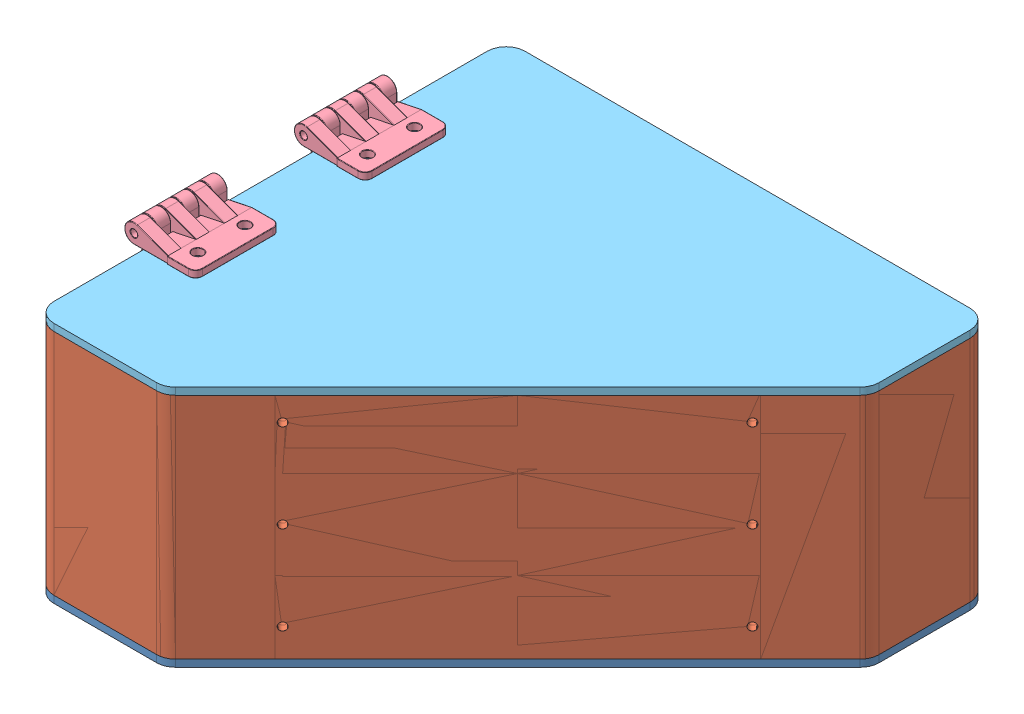
SolidWorks assembly assieme3, configuration Default. Lengths in mm.
Overall size (239.18 111 212.11).
9 component instances, 5 part files, 16 mates.
Components (placement in the parent):
- sotto-1: sotto [Default] at (-155.9057 -26.2592 100) size (205 3 200)
- sopra-1: sopra [Default] at (-155.9057 -26.2592 100) size (237.93 97 212.11)
- middle-1: middle [Default] at (43.7198 44.7408 -93.5026) x (0 0 1) z (0 -1 0) size (187 193 5)
- hinge-2: hinge [Default] at (-155.9057 54.2981 -18) x (0 1 0) z (0 0 1) size (30.44 8 36)
- lid-1: lid [Default] at (-155.9057 73.7408 100) x (1 0 0) z (0 1 0) size (205 200 3)
- hinge-6: hinge [Default] at (-133.4631 76.7408 -53.7) x (-1 0 0) z (0 0 -1) size (30.44 8 36)
- hinge-7: hinge [Default] at (-133.4631 76.7408 18.3) x (-1 0 0) z (0 0 -1) size (30.44 8 36)
- hinge-8: hinge [Default] at (-155.9057 54.2981 54) x (0 1 0) z (0 0 1) size (30.44 8 36)
- sopra-2: sopra [Default] at (-155.9057 -26.2592 100) size (237.93 97 212.11)
Mates (geometry in assembly coordinates):
- Concentrico1: concentric aligned: cylinder of sotto-1 through (-102.1147 -26.2592 97.0813) axis (0 -1 0) radius 1.65; cylinder of sopra-1 through (-102.1147 -26.2592 97.0813) axis (0 -1 0) radius 1.65
- Coincidente1: coincident aligned: plane of sotto-1 through (-155.9057 73.7408 92) normal (-1 0 0); plane of sopra-1 through (-155.9057 73.7408 92) normal (-1 0 0)
- Coincidente2: coincident anti-aligned: plane of sopra-1 through (-135.9057 39.7408 -80) normal (0 1 0); plane of layer2.2-1 through (-141.2802 39.7408 -85.5026) normal (0 -1 0)
- Coincidente5: coincident: plane of sotto-1 through (-155.9057 -23.2592 100.01) normal (0 1 0); line of sopra-1 through (-77.4618 -23.2592 76.5561) axis (0.707107 0 -0.707107)
- Concentrico4: concentric aligned: circle of sopra-1; circle of layer2.2-1
- Coincidente24: coincident anti-aligned: plane of hinge-4 through (-152.9057 88.5408 15) normal (-1 0 0); plane of lid prova-1 through (-104.2195 73.7408 92) normal (0 -1 0)
- Coincidente103: coincident: plane of sopra-1 through (-155.9057 73.7408 92) normal (-1 0 0); plane of hinge-2 through (-155.9057 80.7408 -54) normal (1 0 0)
- Concentrico14: concentric: cylinder of hinge-2 through (-159.9057 80.7408 -54) axis (0 0 1) radius 1.5; cylinder of hinge-6 through (-159.9057 80.7408 -17.7) axis (0 0 -1) radius 1.5
- Coincidente105: coincident anti-aligned: plane of lid prova-1 through (-104.2195 76.7408 92) normal (0 1 0); plane of hinge-6 through (-159.9057 76.7408 -17.7) normal (0 -1 0)
- Coincidente115: coincident: plane of hinge-2 through (-159.9057 80.7408 -53.7) normal (0 0 -1); plane of hinge-6 through (-159.9057 80.7408 -53.7) normal (0 0 -1)
- Distanza9: distance = 8 mm: line of sopra-1 through (-155.9057 73.7408 -62) axis (0 -1 0); plane of hinge-2 through (-159.9057 80.7408 -54) normal (0 0 -1)
- Concentrico15: concentric: cylinder of sopra-1 through (-155.9057 61.2981 26) axis (-1 0 0) radius 1.65; cylinder of hinge-8 through (-155.9057 61.2981 26) axis (-1 0 0) radius 2.25
- Concentrico16: concentric: cylinder of sopra-1 through (-155.9057 61.2981 46) axis (-1 0 0) radius 1.65; cylinder of hinge-8 through (-155.9057 61.2981 46) axis (-1 0 0) radius 2.25
- Concentrico17: concentric aligned: cylinder of lid prova-1 through (-140.4631 76.7408 -45.7) axis (0 1 0) radius 1.65; circle of hinge-6
- Concentrico18: concentric aligned: cylinder of lid prova-1 through (-140.4631 76.7408 -25.7) axis (0 1 0) radius 1.65; cylinder of hinge-6 through (-140.4631 76.7408 -25.7) axis (0 1 0) radius 2.25
- AngoloLimite2: limit planar angle = 0 rad anti-aligned: plane of lid prova-1 through (-104.2195 73.7408 92) normal (0 -1 0); plane of sopra-1 through (-147.9057 73.7408 -92) normal (0 1 0)
